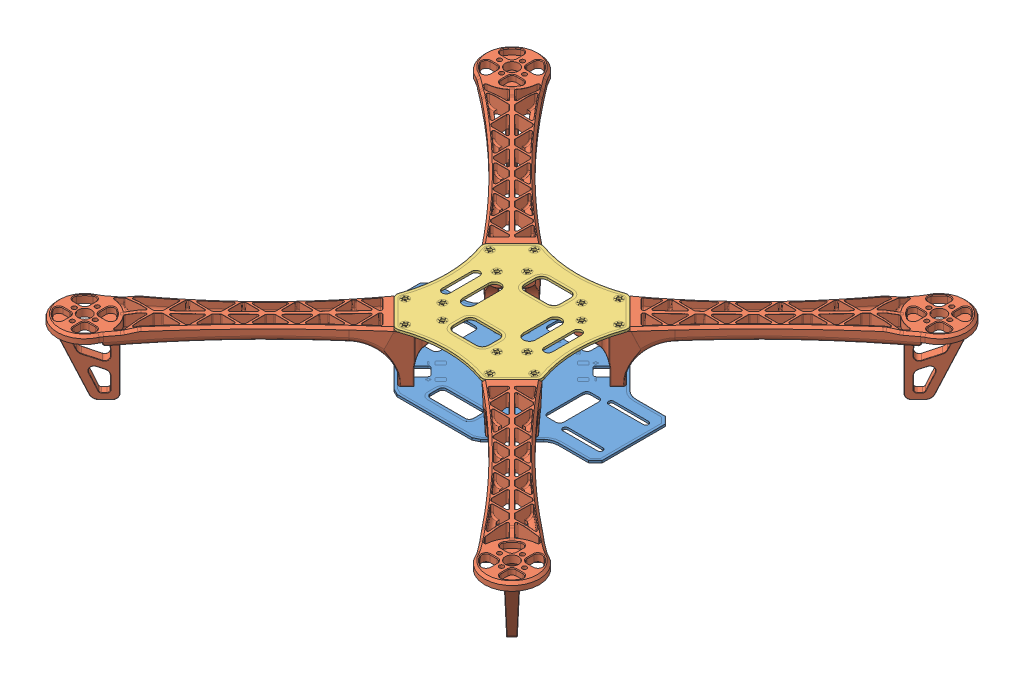
SolidWorks assembly Assembly, configuration Default. Lengths in mm.
Overall size (375.45 55.34 375.45).
6 component instances, 3 part files, 18 mates.
Components (placement in the parent):
- Base bottom-1: Base bottom [Default] at (67.5563 86.9564 146.6689) size (182 1.6 118)
- arm-1: arm [Default] at (165.9237 126.3564 245.0469) x (-0.707107 0 0.707107) z (-0.707107 0 -0.707107) size (40.75 55.34 213.92)
- arm-2: arm [Default] at (-30.8217 126.3564 245.0362) x (-0.707107 0 -0.707107) z (0.707107 0 -0.707107) size (40.75 55.34 213.92)
- arm-3: arm [Default] at (165.9344 126.3564 48.3015) x (0.707107 0 0.707107) z (-0.707107 0 0.707107) size (40.75 55.34 213.92)
- arm-4: arm [Default] at (-30.811 126.3564 48.2908) x (0.707107 0 -0.707107) z (0.707107 0 0.707107) size (40.75 55.34 213.92)
- Base Top-1: Base Top [Default] at (67.5563 125.3865 146.6689) size (108.15 1.65 108.15)
Mates (geometry in assembly coordinates):
- Coincident2: coincident anti-aligned: plane of Base bottom-1 through (4.0563 87.7564 186.9169) normal (0 1 0); plane of arm-1 through (104.3913 87.7564 193.9796) normal (0 -1 0)
- Coincident3: coincident anti-aligned: line of Base bottom-1 through (99.5883 86.1554 193.1965) axis (0 1 0); line of arm-1 through (99.5883 92.7564 193.1965) axis (0 -1 0)
- Coincident4: coincident anti-aligned: line of Base bottom-1 through (114.084 86.1554 178.7008) axis (0 1 0); line of arm-1 through (114.084 92.7564 178.7008) axis (0 -1 0)
- Coincident5: coincident anti-aligned: plane of Base bottom-1 through (4.0563 87.7564 186.9169) normal (0 1 0); plane of arm-2 through (35.6249 87.7564 197.7501) normal (0 -1 0)
- Coincident6: coincident anti-aligned: line of Base bottom-1 through (21.0287 86.1554 178.7008) axis (0 1 0); line of arm-2 through (21.0287 92.7564 178.7008) axis (0 -1 0)
- Coincident7: coincident anti-aligned: line of Base bottom-1 through (35.5244 86.1554 193.1965) axis (0 1 0); line of arm-2 through (35.5244 92.7564 193.1965) axis (0 -1 0)
- Coincident8: coincident anti-aligned: line of Base bottom-1 through (114.084 86.1554 114.6369) axis (0 1 0); line of arm-3 through (114.084 92.7564 114.6369) axis (0 -1 0)
- Coincident9: coincident anti-aligned: plane of Base bottom-1 through (4.0563 87.7564 186.9169) normal (0 1 0); plane of arm-3 through (114.8671 87.7564 109.8339) normal (0 -1 0)
- Coincident10: coincident anti-aligned: line of Base bottom-1 through (99.5883 86.1554 100.1412) axis (0 1 0); line of arm-3 through (99.5883 92.7564 100.1412) axis (0 -1 0)
- Coincident13: coincident anti-aligned: line of Base bottom-1 through (35.5244 86.1554 100.1412) axis (0 1 0); line of arm-4 through (35.5244 92.7564 100.1412) axis (0 -1 0)
- Coincident14: coincident anti-aligned: plane of Base bottom-1 through (4.0563 87.7564 186.9169) normal (0 1 0); plane of arm-4 through (30.7214 87.7564 99.3581) normal (0 -1 0)
- Coincident15: coincident anti-aligned: line of Base bottom-1 through (21.0287 86.1554 114.6369) axis (0 1 0); line of arm-4 through (21.0287 92.7564 114.6369) axis (0 -1 0)
- Coincident16: coincident anti-aligned: plane of arm-1 through (121.2204 124.5615 177.999) normal (0 1 0); plane of mount1-1 through (18.1568 124.5615 114.9285) normal (0 -1 0)
- Coincident17: coincident aligned: line of arm-1 through (99.0226 119.5615 194.7521) axis (0 1 0); line of mount1-1 through (99.0226 124.5615 194.7521) axis (0 1 0)
- Coincident18: coincident aligned: line of arm-1 through (115.6396 119.5615 178.1351) axis (0 1 0); line of mount1-1 through (115.6396 124.5615 178.1351) axis (0 1 0)
- Concentric1: concentric: circle of arm-1; circle of Base Top-1
- Concentric2: concentric: circle of arm-1; circle of Base Top-1
- Coincident19: coincident anti-aligned: plane of arm-1 through (121.2204 124.5615 177.999) normal (0 1 0); plane of Base Top-1 through (99.2967 124.5615 97.2693) normal (0 -1 0)
